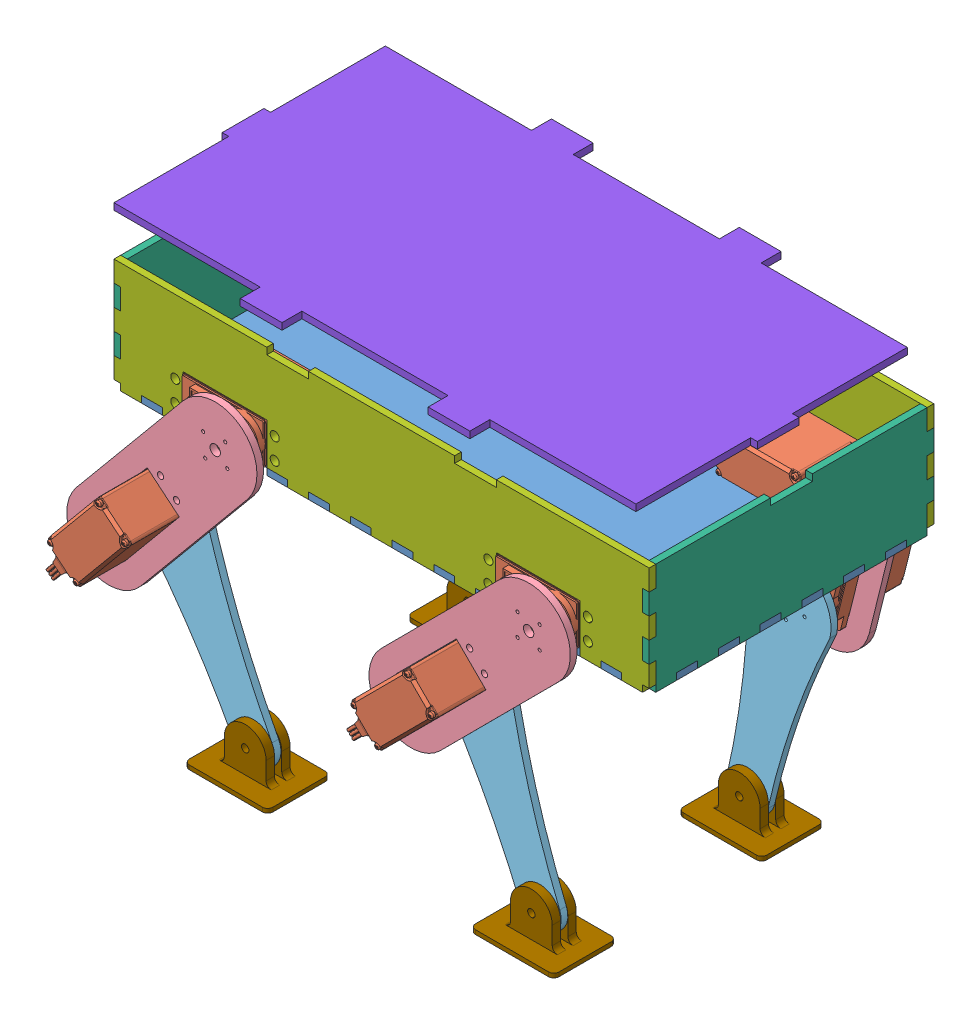
SolidWorks assembly Tertrabot, configuration Défaut. Lengths in mm.
Overall size (312.26 237.25 213.21).
38 component instances, 9 part files, 59 mates.
Components (placement in the parent):
- Body-1: Body [Défaut] at (-100.0444 -1.6355 50.0049) size (256.35 3.17 136.35)
- moteur-1: moteur [Défaut] at (100.0166 1.5395 41.5213) x (0 1 0) z (1 0 0) size (19.88 42.12 58.23)
- moteur-2: moteur [Défaut] at (-50.1054 1.5395 41.5213) x (0 1 0) z (1 0 0) size (19.88 42.12 58.23)
- moteur-3: moteur [Défaut] at (-50.1054 21.3515 -71.5115) x (0 -1 0) z (1 0 0) size (19.88 42.12 58.23)
- moteur-4: moteur [Défaut] at (100.0166 21.3515 -71.5115) x (0 -1 0) z (1 0 0) size (19.88 42.12 58.23)
- hs-422_horn_4wings_sws-1: hs-422_horn_4wings_sws [Défaut] at (110.3036 11.4455 62.912) x (0.708336 -0.705875 0) z (-0.705875 -0.708336 0) size (29 5 31)
- hs-422_horn_4wings_sws-2: hs-422_horn_4wings_sws [Défaut] at (-39.8184 11.4455 62.912) x (0.769155 -0.639062 0) z (-0.639062 -0.769155 0) size (29 5 31)
- hs-422_horn_4wings_sws-3: hs-422_horn_4wings_sws [Défaut] at (-39.8184 11.4455 -92.9021) x (0.775659 -0.631153 0) z (0.631153 0.775659 0) size (29 5 31)
- hs-422_horn_4wings_sws-4: hs-422_horn_4wings_sws [Défaut] at (110.3036 11.4455 -92.9021) x (0.240722 0.970594 0) z (-0.970594 0.240722 0) size (29 5 31)
- Leg-1: Leg [Défaut] at (-80.0902 -51.4252 66.2077) x (0.46834 -0.883548 0) z (0.883548 0.46834 0) size (165.68 47.79 122.53) (flexible)
  - hs-422_horn_4wings_sws-1: hs-422_horn_4wings_sws [Défaut] at (-9.849 16.7173 0) size (29 5 31)
  - moteur-1: moteur [Défaut] at (-4.5992 -4.6733 13.2812) x (-0.924868 0 -0.380287) z (0.380287 0 -0.924868) size (19.88 42.12 58.23)
  - thigh-1: thigh [Défaut] at (-21.3353 -1.8793 27.6879) x (0.380287 0 -0.924868) z (0.924868 0 0.380287) size (120 3.17 40)
  - tibia-1: tibia [Défaut] at (30.5233 19.2173 0) size (120 3.17 40)
- Leg-2: Leg [Défaut] at (64.4482 -47.5642 66.2077) x (0.37922 -0.925307 0) z (0.925307 0.37922 0) size (165.68 47.79 122.53) (flexible)
  - hs-422_horn_4wings_sws-1: hs-422_horn_4wings_sws [Défaut] at (-9.849 16.7173 0) size (29 5 31)
  - moteur-1: moteur [Défaut] at (-4.7067 -4.6733 13.3232) x (-0.921766 0 -0.387746) z (0.387746 0 -0.921766) size (19.88 42.12 58.23)
  - thigh-1: thigh [Défaut] at (-21.5586 -1.8793 27.5942) x (0.387746 0 -0.921766) z (0.921766 0 0.387746) size (120 3.17 40)
  - tibia-1: tibia [Défaut] at (30.5233 19.2173 0) size (120 3.17 40)
- Leg-3: Leg [Défaut] at (-81.2389 -52.4252 -96.1978) x (0.309954 -0.950751 0) z (-0.950751 -0.309954 0) size (165.68 47.79 122.53)
  - hs-422_horn_4wings_sws-1: hs-422_horn_4wings_sws [Défaut] at (-9.849 16.7173 0) size (29 5 31)
  - moteur-1: moteur [Défaut] at (-23.7487 -4.6733 -3.2787) x (0.840488 0 -0.54183) z (0.54183 0 0.840488) size (19.88 42.12 58.23)
  - thigh-1: thigh [Défaut] at (-26.0117 -1.8793 -25.2452) x (0.54183 0 0.840488) z (-0.840488 0 0.54183) size (120 3.17 40)
  - tibia-1: tibia [Défaut] at (30.5233 19.2173 0) size (120 3.17 40)
- Leg-4: Leg [Défaut] at (91.0902 -66.4142 -96.1978) x (-0.222139 -0.975015 0) z (-0.975015 0.222139 0) size (165.68 47.79 122.53) (flexible)
  - hs-422_horn_4wings_sws-1: hs-422_horn_4wings_sws [Défaut] at (-9.849 16.7173 0) size (29 5 31)
  - moteur-1: moteur [Défaut] at (-20.3233 -4.6733 9.7077) x (0.019101 0 -0.999818) z (0.999818 0 0.019101) size (19.88 42.12 58.23)
  - thigh-1: thigh [Défaut] at (-39.8175 -1.8793 -0.6666) x (0.999818 0 0.019101) z (-0.019101 0 0.999818) size (120 3.17 40)
  - tibia-1: tibia [Défaut] at (30.5233 19.2173 0) size (120 3.17 40)
- Face-1: Face [Défaut] at (153.1306 1.5395 -79.9951) x (0 0 1) z (-1 0 0) size (136.35 53.17 3.17)
- Face-2: Face [Défaut] at (-100.0444 1.5395 -79.9951) x (0 0 1) z (-1 0 0) size (136.35 53.17 3.17)
- Mur-1: Mur [Défaut] at (149.9556 1.5395 53.1799) x (0 0 -1) z (1 0 0) size (3.17 53.17 256.35)
- Mur-2: Mur [Défaut] at (-100.0444 1.5395 -83.1701) x (0 0 1) z (-1 0 0) size (3.17 53.17 256.35)
- Top-1: Top [Défaut] at (-100.0444 74.9165 56.3549) size (256.35 3.17 149.05)
- foot-1: foot [Défaut] at (-42.5523 -135.2425 45.2403) x (0 0 1) z (-1 0 0) size (30 23 40)
- foot-2: foot [Défaut] at (-56.3958 -141.6289 -75.2305) x (0 0 1) z (-1 0 0) size (30 23 40)
- foot-3: foot [Défaut] at (94.843 -134.7285 45.5653) x (0 0 1) z (-1 0 0) size (30 23 40)
- foot-4: foot [Défaut] at (73.2856 -157.5626 -75.5555) x (0 0 1) z (-1 0 0) size (30 23 40)
Mates (geometry in assembly coordinates):
- Coïncidente1: coincident anti-aligned: plane of Body-1 through (-100.0444 1.5395 50.0049) normal (0 1 0); plane of moteur-1 through (100.0166 1.5395 41.5213) normal (0 -1 0)
- Distance1: distance = 30 mm aligned: plane of moteur-1 through (119.9556 21.3515 41.5213) normal (1 0 0); plane of Body-1 through (149.9556 1.5395 50.0049) normal (1 0 0)
- Coïncidente5: coincident anti-aligned: plane of Body-1 through (-100.0444 1.5395 50.0049) normal (0 1 0); plane of moteur-2 through (-50.1054 1.5395 41.5213) normal (0 -1 0)
- Coïncidente8: coincident anti-aligned: plane of Body-1 through (-100.0444 1.5395 50.0049) normal (0 1 0); plane of moteur-4 through (100.0166 1.5395 -71.5115) normal (0 -1 0)
- Coïncidente10: coincident aligned: plane of moteur-1 through (119.9556 21.3515 41.5213) normal (1 0 0); plane of moteur-4 through (119.9556 1.5395 -71.5115) normal (1 0 0)
- Coïncidente11: coincident anti-aligned: plane of Body-1 through (-100.0444 1.5395 50.0049) normal (0 1 0); plane of moteur-3 through (-50.1054 1.5395 -71.5115) normal (0 -1 0)
- Coïncidente13: coincident aligned: plane of moteur-2 through (-70.0444 21.3515 41.5213) normal (-1 0 0); plane of moteur-3 through (-70.0444 1.5395 -71.5115) normal (-1 0 0)
- Coaxiale1: concentric anti-aligned: circle of moteur-4; circle of hs-422_horn_4wings_sws-4
- Coïncidente14: coincident anti-aligned: plane of moteur-4 through (100.0166 1.5395 -92.9021) normal (0 0 -1); plane of hs-422_horn_4wings_sws-4 through (107.4149 -0.2017 -92.9021) normal (0 0 1)
- Coaxiale2: concentric anti-aligned: circle of moteur-3; circle of hs-422_horn_4wings_sws-3
- Coïncidente15: coincident anti-aligned: plane of moteur-3 through (-50.1054 1.5395 -92.9021) normal (0 0 -1); plane of hs-422_horn_4wings_sws-3 through (-49.1263 19.0193 -92.9021) normal (0 0 1)
- Coaxiale3: concentric anti-aligned: circle of moteur-2; circle of hs-422_horn_4wings_sws-2
- Coïncidente16: coincident anti-aligned: plane of moteur-2 through (-50.1054 21.3515 62.912) normal (0 0 1); plane of hs-422_horn_4wings_sws-2 through (-49.0483 19.1142 62.912) normal (0 0 -1)
- Coaxiale4: concentric anti-aligned: circle of moteur-1; circle of hs-422_horn_4wings_sws-1
- Coïncidente17: coincident anti-aligned: plane of moteur-1 through (100.0166 21.3515 62.912) normal (0 0 1); plane of hs-422_horn_4wings_sws-1 through (101.8035 19.916 62.912) normal (0 0 -1)
- Coaxiale5: concentric aligned: circle of hs-422_horn_4wings_sws-2; circle of Leg-1/thigh-1
- Coaxiale6: concentric anti-aligned: cylinder of hs-422_horn_4wings_sws-2; cylinder of Leg-1/thigh-1 through (-35.0255 17.2141 64.912) axis (0 0 1) radius 0.75
- Coaxiale7: concentric aligned: circle of hs-422_horn_4wings_sws-1; circle of Leg-2/thigh-1
- Coaxiale8: concentric anti-aligned: circle of hs-422_horn_4wings_sws-1; circle of Leg-2/thigh-1
- Coaxiale9: concentric aligned: circle of hs-422_horn_4wings_sws-4; circle of Leg-4/thigh-1
- Coaxiale10: concentric anti-aligned: circle of hs-422_horn_4wings_sws-4; circle of Leg-4/thigh-1
- Coaxiale11: concentric aligned: circle of hs-422_horn_4wings_sws-3; circle of Leg-3/thigh-1
- Coaxiale12: concentric anti-aligned: circle of hs-422_horn_4wings_sws-3; circle of Leg-3/thigh-1
- Coïncidente22: coincident anti-aligned: plane of hs-422_horn_4wings_sws-2 through (-49.0483 19.1142 64.912) normal (0 0 1); plane of Leg-1/thigh-1 through (-39.8184 11.4455 64.912) normal (0 0 -1)
- Coïncidente23: coincident anti-aligned: plane of hs-422_horn_4wings_sws-1 through (101.8035 19.916 64.912) normal (0 0 1); plane of Leg-2/thigh-1 through (110.3036 11.4455 64.912) normal (0 0 -1)
- Coïncidente24: coincident anti-aligned: plane of hs-422_horn_4wings_sws-4 through (107.4149 -0.2017 -94.9021) normal (0 0 -1); plane of Leg-4/thigh-1 through (110.3036 11.4455 -94.9021) normal (0 0 1)
- Coïncidente25: coincident anti-aligned: plane of hs-422_horn_4wings_sws-3 through (-49.1263 19.0193 -94.9021) normal (0 0 -1); plane of Leg-3/thigh-1 through (-39.8184 11.4455 -94.9021) normal (0 0 1)
- Coïncidente26: coincident anti-aligned: plane of ArduinoMega_STEP_AP203.step-1 through (-22.1291 1.5395 8.4211) normal (0 -1 0); plane of Body-1 through (-100.0444 1.5395 50.0049) normal (0 1 0)
- Coïncidente33: coincident anti-aligned: plane of moteur-3 through (-50.1054 21.3515 -71.5115) normal (0 1 0); plane of Raspberry Pi 3 Light Version-1 through (-70.0444 21.3515 11.0049) normal (0 -1 0)
- Coïncidente34: coincident aligned: plane of moteur-3 through (-70.0444 1.5395 -71.5115) normal (-1 0 0); plane of Raspberry Pi 3 Light Version-1 through (-70.0444 20.9215 -42.0051) normal (-1 0 0)
- Distance6: distance = 35 mm aligned: plane of ? through (79.4709 1.5395 -44.9951) normal (0 0 -1); plane of Body-1 through (-100.0444 1.5395 -79.9951) normal (0 0 -1)
- Coïncidente37: coincident aligned: plane of ArduinoMega_STEP_AP203.step-1 through (79.4709 1.5395 -44.9951) normal (0 0 -1); plane of Raspberry Pi 3 Light Version-1 through (11.8897 20.9215 -44.9951) normal (0 0 -1)
- Distance8: distance = 30 mm: plane of assembly; plane of Body-1 through (-100.0444 1.5395 50.0049) normal (-1 0 0); plane of moteur-2 through (-70.0444 21.3515 41.5213) normal (-1 0 0)
- Coïncidente43: coincident anti-aligned: plane of Body-1 through (-100.0444 1.5395 50.0049) normal (0 0 1); plane of Mur-1 through (149.9556 1.5395 50.0049) normal (0 0 -1)
- Coïncidente44: coincident anti-aligned: plane of Body-1 through (-100.0444 1.5395 50.0049) normal (0 1 0); plane of Mur-1 through (149.9556 1.5395 50.0049) normal (0 -1 0)
- Coïncidente45: coincident anti-aligned: plane of Body-1 through (139.9556 -1.6355 50.0049) normal (1 0 0); plane of Mur-1 through (139.9556 1.5395 53.1799) normal (-1 0 0)
- Coïncidente46: coincident anti-aligned: plane of Body-1 through (-100.0444 1.5395 -79.9951) normal (0 0 -1); plane of Mur-2 through (-100.0444 1.5395 -79.9951) normal (0 0 1)
- Coïncidente47: coincident anti-aligned: plane of Body-1 through (-100.0444 1.5395 50.0049) normal (0 1 0); plane of Mur-2 through (-100.0444 1.5395 -79.9951) normal (0 -1 0)
- Coïncidente48: coincident anti-aligned: plane of Body-1 through (139.9556 -1.6355 -79.9951) normal (1 0 0); plane of Mur-2 through (139.9556 1.5395 -83.1701) normal (-1 0 0)
- Coïncidente49: coincident anti-aligned: plane of Body-1 through (149.9556 1.5395 50.0049) normal (1 0 0); plane of Face-1 through (149.9556 1.5395 -79.9951) normal (-1 0 0)
- Coïncidente50: coincident anti-aligned: plane of Body-1 through (-100.0444 1.5395 50.0049) normal (0 1 0); plane of Face-1 through (149.9556 1.5395 -79.9951) normal (0 -1 0)
- Coïncidente51: coincident aligned: plane of Face-1 through (153.1306 41.5395 53.1799) normal (0 0 1); plane of Mur-1 through (149.9556 1.5395 53.1799) normal (0 0 1)
- Coïncidente52: coincident anti-aligned: plane of Body-1 through (-100.0444 1.5395 50.0049) normal (-1 0 0); plane of Face-2 through (-100.0444 1.5395 -79.9951) normal (1 0 0)
- Coïncidente53: coincident anti-aligned: plane of Body-1 through (-100.0444 1.5395 50.0049) normal (0 1 0); plane of Face-2 through (-103.2194 1.5395 -79.9951) normal (0 -1 0)
- Coïncidente54: coincident aligned: plane of Face-2 through (-100.0444 41.5395 -83.1701) normal (0 0 -1); plane of Mur-2 through (-100.0444 1.5395 -83.1701) normal (0 0 -1)
- Coïncidente55: coincident aligned: plane of Mur-2 through (-100.0444 1.5395 -83.1701) normal (0 0 -1); plane of Top-1 through (79.9556 74.9165 -83.1701) normal (0 0 -1)
- Coïncidente56: coincident aligned: plane of Face-2 through (-103.2194 1.5395 -79.9951) normal (-1 0 0); plane of Top-1 through (-103.2194 74.9165 -18.6451) normal (-1 0 0)
- Coïncidente58: coincident anti-aligned: plane of moteur-1 through (110.4314 11.9535 50.0049) normal (0 0 1); plane of Mur-1 through (149.9556 1.5395 50.0049) normal (0 0 -1)
- Coïncidente59: coincident anti-aligned: plane of moteur-2 through (-39.6906 11.9535 50.0049) normal (0 0 1); plane of Mur-1 through (149.9556 1.5395 50.0049) normal (0 0 -1)
- Coïncidente60: coincident anti-aligned: plane of moteur-4 through (89.623 21.3515 -79.9951) normal (0 0 -1); plane of Mur-2 through (-100.0444 1.5395 -79.9951) normal (0 0 1)
- Coïncidente61: coincident anti-aligned: plane of moteur-3 through (-60.499 21.3515 -79.9951) normal (0 0 -1); plane of Mur-2 through (-100.0444 1.5395 -79.9951) normal (0 0 1)
- Coaxiale13: concentric anti-aligned: circle of Leg-1/tibia-1; circle of foot-1
- Coïncidente62: coincident anti-aligned: plane of Leg-1/tibia-1 through (-249.1727 -180.8342 46.9903) normal (0 0 1); plane of foot-1 through (-32.5523 -122.2425 46.9903) normal (0 0 -1)
- Coaxiale14: concentric anti-aligned: circle of Leg-3/tibia-1; circle of foot-2
- Coïncidente63: coincident anti-aligned: plane of Leg-3/tibia-1 through (129.3141 -20.7546 -76.9805) normal (0 0 -1); plane of foot-2 through (-46.3958 -128.6289 -76.9805) normal (0 0 1)
- Coaxiale15: concentric anti-aligned: circle of Leg-2/tibia-1; cylinder of foot-3 through (94.843 -121.7285 34.7864) axis (0 0 1) radius 1.778
- Coïncidente64: coincident anti-aligned: plane of Leg-2/tibia-1 through (-116.5363 -159.7258 43.8153) normal (0 0 -1); plane of foot-3 through (104.843 -121.7285 43.8153) normal (0 0 1)
- Coaxiale16: concentric anti-aligned: cylinder of Leg-4/tibia-1 through (73.2856 -144.5626 -76.9815) axis (0 0 1) radius 2.54; circle of foot-4
- Coïncidente65: coincident anti-aligned: plane of Leg-4/tibia-1 through (288.035 -147.336 -73.8055) normal (0 0 1); plane of foot-4 through (83.2856 -144.5626 -73.8055) normal (0 0 -1)
